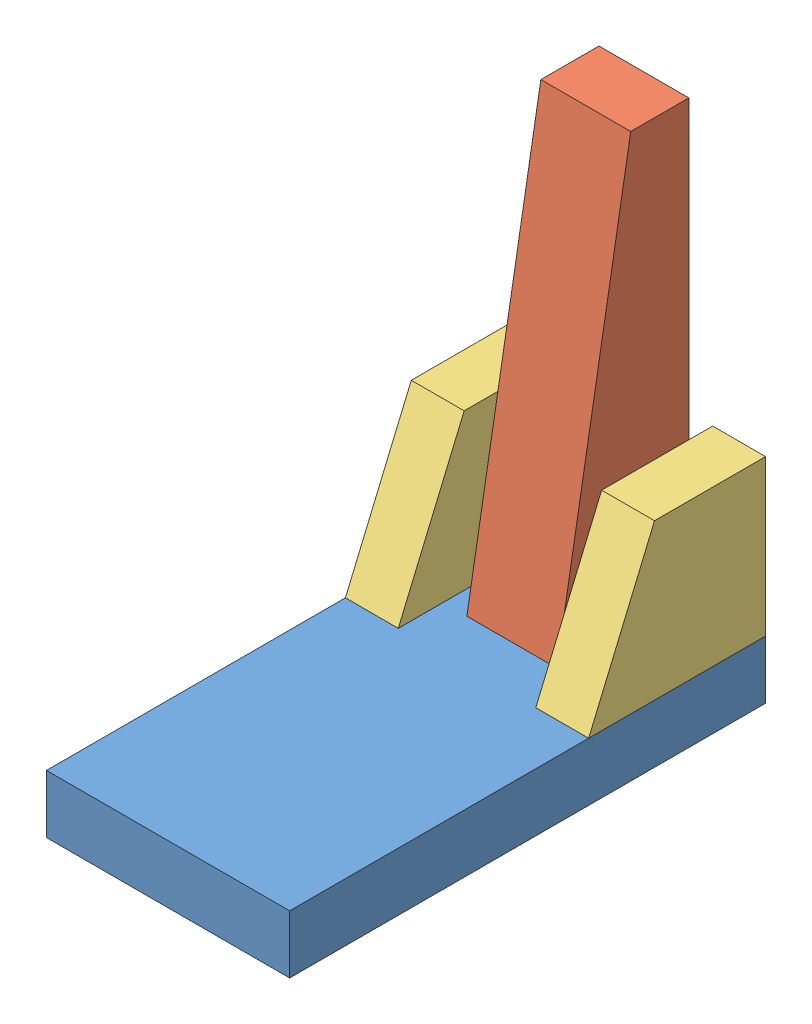
SolidWorks assembly low_detail_assembly, configuration Default. Lengths in mm.
Overall size (460 919 900).
4 component instances, 3 part files, 11 mates.
Components (placement in the parent):
- base_low_detail-1: base_low_detail [Default] at (-2.0876 -63.7905 7.0737) size (460 110 900)
- tower_low_detail-1: tower_low_detail [Default] at (-87.0876 45.2095 -442.9263) size (170 810 250)
- sides_low_detail-1: sides_low_detail [Default] at (127.9124 45.2095 -442.9263) size (100 295 335)
- sides_low_detail-2: sides_low_detail [Default] at (-232.0876 45.2095 -442.9263) size (100 295 335)
Mates (geometry in assembly coordinates):
- Coincident1: coincident: plane of base_low_detail-1 through (227.9124 46.2095 -442.9263) normal (0 0 -1); plane of tower_low_detail-1 through (82.9124 45.2095 -442.9263) normal (0 0 -1)
- Width1: width: plane of base_low_detail-1 through (227.9124 46.2095 457.0737) normal (1 0 0); plane of base_low_detail-1 through (-232.0876 46.2095 457.0737) normal (-1 0 0); plane of tower_low_detail-1 through (-87.0876 45.2095 -442.9263) normal (-1 0 0); plane of tower_low_detail-1 through (82.9124 45.2095 -442.9263) normal (1 0 0)
- Distance2: distance = 1 mm: plane of base_low_detail-1 through (-2.0876 46.2095 7.0737) normal (0 1 0); plane of tower_low_detail-1 through (82.9124 45.2095 -192.9263) normal (0 -1 0)
- Coincident3: coincident: plane of base_low_detail-1 through (-2.0876 46.2095 7.0737) normal (0 1 0); plane of ? through (27.9124 46.2095 -62.7233) normal (0 -1 0)
- Width2: width: plane of base_low_detail-1 through (-232.0876 46.2095 457.0737) normal (-1 0 0); plane of base_low_detail-1 through (227.9124 46.2095 457.0737) normal (1 0 0); plane of ? through (27.9124 46.2095 42.2767) normal (1 0 0); plane of ? through (-32.0876 46.2095 42.2767) normal (-1 0 0)
- Coincident4: coincident: plane of base_low_detail-1 through (227.9124 46.2095 -442.9263) normal (0 0 -1); plane of sides_low_detail-1 through (227.9124 -73.915 -442.9263) normal (0 0 -1)
- Coincident6: coincident: plane of base_low_detail-1 through (227.9124 46.2095 -442.9263) normal (0 0 -1); plane of sides_low_detail-2 through (-132.0876 45.2095 -442.9263) normal (0 0 -1)
- Coincident7: coincident: plane of base_low_detail-1 through (227.9124 46.2095 457.0737) normal (1 0 0); plane of sides_low_detail-1 through (227.9124 45.2095 -442.9263) normal (1 0 0)
- Coincident8: coincident: plane of base_low_detail-1 through (-232.0876 46.2095 457.0737) normal (-1 0 0); plane of sides_low_detail-2 through (-232.0876 45.2095 -442.9263) normal (-1 0 0)
- Coincident9: coincident: plane of sides_low_detail-1 through (227.9124 45.2095 -107.9263) normal (0 -1 0); plane of sides_low_detail-2 through (-132.0876 45.2095 -107.9263) normal (0 -1 0)
- Distance3: distance = 1 mm: plane of sides_low_detail-2 through (-132.0876 45.2095 -107.9263) normal (0 -1 0); plane of base_low_detail-1 through (-2.0876 46.2095 7.0737) normal (0 1 0)
